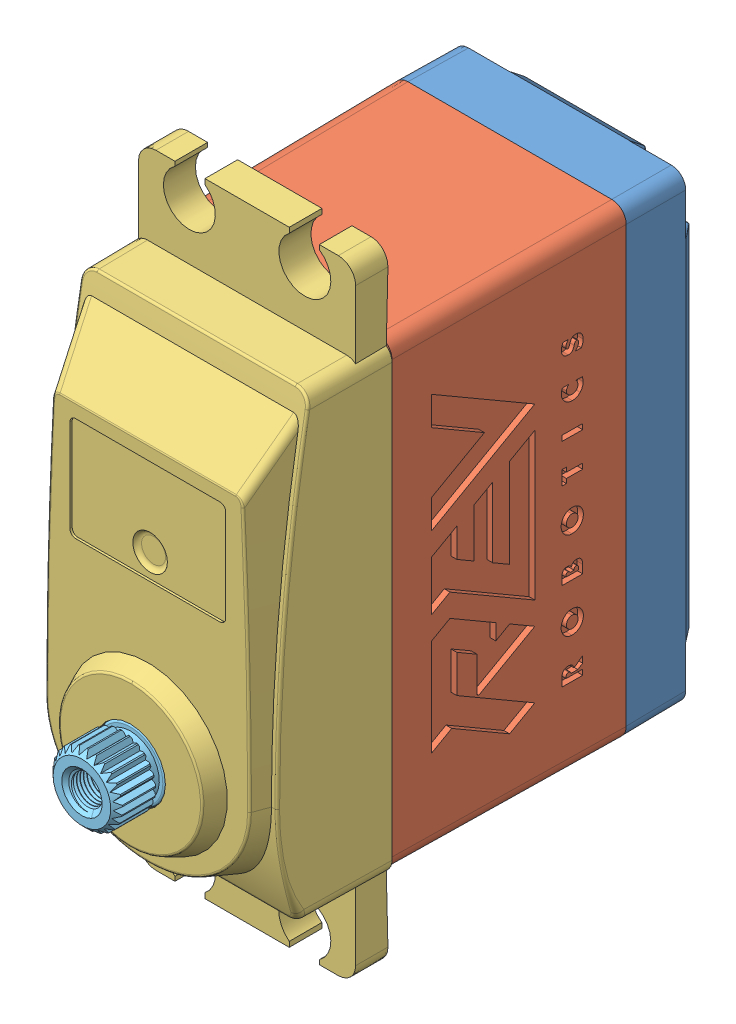
SolidWorks assembly PART_ASSEM_ServoSmartRobot, configuration Default. Lengths in mm.
Overall size (23.11 54 43.55).
5 component instances, 5 part files, 10 mates.
Components (placement in the parent):
- PART_ServoSmartRobot_A-1: PART_ServoSmartRobot_A [Default] at (-57.1769 6.2471 -37.85) x (-1 0 0) z (0 0 -1) size (20.15 40.13 8.5)
- PART_ServoSmartRobot_E-1: PART_ServoSmartRobot_E [Default] at (-57.1765 6.2367 -37.9) x (-1 0 0) z (0 0 -1) size (20.24 40.15 20.1)
- PART_ServoSmartRobot_C-1: PART_ServoSmartRobot_C [Default] at (-57.1778 6.0095 -37.95) x (-1 0 0) z (0 0 -1) size (19.8 54 13.28)
- PART_ServoSmartRobot_B-1: PART_ServoSmartRobot_B [Default] at (-66.9629 -6.3464 -37.9) x (0.229124 -0.973397 0) z (0 0 -1) size (9 9 4.4)
- PART_ServoSmartRobot_D-1: PART_ServoSmartRobot_D [Default] at (-57.1778 -4.0431 -7.9) x (-0.452689 0.891669 0) z (0 0 -1) size (17.2 17.19 14.7)
Mates (geometry in assembly coordinates):
- Concentric1: concentric anti-aligned: cylinder of PART_ServoSmartRobot_B-1 through (-37.5583 2.6782 -6.62) axis (0 0 1) radius 2; cylinder of PART_ServoSmartRobot_D-1 through (-37.5583 2.6782 -9) axis (0 0 -1) radius 2
- Coincident3: coincident anti-aligned: plane of PART_ServoSmartRobot_B-1 through (-37.5583 2.6782 -5.6) normal (0 0 1); plane of PART_ServoSmartRobot_D-1 through (-37.5583 2.6782 -5.6) normal (0 0 -1)
- Concentric6: concentric anti-aligned: cylinder of PART_ServoSmartRobot_C-1 through (-37.5583 2.6782 -37.95) axis (0 0 -1) radius 3.025; cylinder of PART_ServoSmartRobot_D-1 through (-37.5583 2.6782 -2.3) axis (0 0 1) radius 3
- Coincident8: coincident aligned: plane of PART_ServoSmartRobot_C-1 through (-46.4833 7.3043 1.5) normal (0 0 1); plane of PART_ServoSmartRobot_D-1 through (-37.5583 2.6782 1.5) normal (0 0 1)
- Coincident9: coincident aligned: line of PART_ServoSmartRobot_E-1 through (-67.7981 7.2029 -11.25) axis (0.887824 -0.460184 0); line of PART_ServoSmartRobot_C-1 through (-67.6175 7.1093 -11.25) axis (0.887824 -0.460184 0)
- Coincident12: coincident aligned: line of PART_ServoSmartRobot_E-1 through (-32.9973 -9.4274 -11.25) axis (0.460184 0.887824 0); line of PART_ServoSmartRobot_C-1 through (-33.343 -10.0944 -11.25) axis (0.460184 0.887824 0)
- Coincident13: coincident anti-aligned: line of PART_ServoSmartRobot_A-1 through (-68.5691 8.8129 -31.35) axis (0.460184 0.887824 0); line of PART_ServoSmartRobot_E-1 through (-60.4465 24.4838 -31.35) axis (-0.460184 -0.887824 0)
- Coincident14: coincident anti-aligned: line of PART_ServoSmartRobot_A-1 through (-34.6257 -10.1888 -31.35) axis (-0.887824 0.460184 0); line of PART_ServoSmartRobot_E-1 through (-68.0346 7.1279 -31.35) axis (0.887824 -0.460184 0)
- Parallel4: parallel aligned: plane of PART_ServoSmartRobot_C-1 through (-46.4833 7.3043 0) normal (0 0 1); plane of assembly through (0 0 0) normal (0 0 1)
- Perpendicular3: perpendicular: plane of PART_ServoSmartRobot_E-1 through (-47.2765 27.091 -11.25) normal (0.999962 0 0.008727); plane of assembly
